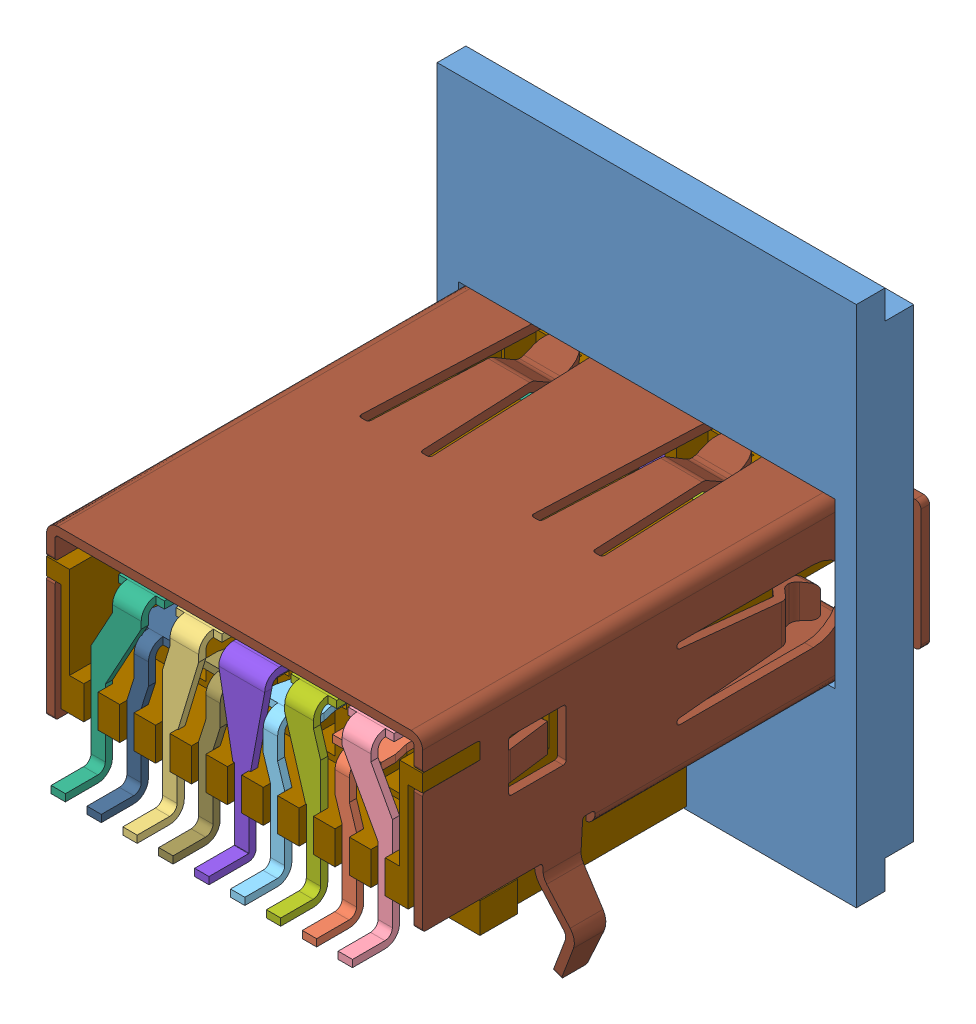
SolidWorks assembly Keystone-USB3-A, configuration Standard. Lengths in mm.
Overall size (15.1 18.2 17.8).
13 component instances, 12 part files, 3 mates.
Components (placement in the parent):
- Keystone-USB-3-Pannel-1: Keystone-USB-3-Pannel [Standard] at (-0.2593 -6.7378 17.2) size (14.6 18.2 2)
- USB3-A-1: USB3-A [Standard] at (-7.5593 2.2822 29.56) x (0 0 -1) z (0 1 0) size (17.8 15.1 10.24)
  - USB3-A-Pin-4-1: USB3-A-Pin-4 [Standard] at origin size (12.71 1.7 4.79)
  - USB3-A-Pin-8-1: USB3-A-Pin-8 [Standard] at origin size (16.44 1.6 5.89)
  - USB3-A-Pin-5-1: USB3-A-Pin-5 [Standard] at origin size (16.44 2.05 5.89)
  - USB3-A-Pin-3-1: USB3-A-Pin-3 [Standard] at origin size (12.71 1.7 4.79)
  - USB3-A-Pin-9-1: USB3-A-Pin-9 [Standard] at origin size (16.44 2.05 5.89)
  - USB3-A-Pin-6-1: USB3-A-Pin-6 [Standard] at origin size (16.44 1.6 5.89)
  - USB3-A-Pin-7-1: USB3-A-Pin-7 [Standard] at origin size (16.44 1.6 5.89)
  - USB3-A-Inner-Plastic-1: USB3-A-Inner-Plastic [Standard] at origin size (16 13.1 7.94)
  - USB3-A-Pin-1-1: USB3-A-Pin-1 [Standard] at origin size (12.71 1.7 4.79)
  - USB3-A-Outer-Shell-1: USB3-A-Outer-Shell [Standard] at origin size (16.66 15.1 10.24)
  - USB3-A-Pin-2-1: USB3-A-Pin-2 [Standard] at origin size (12.71 1.7 4.79)
Mates (geometry in assembly coordinates):
- Deckungsgleich1: coincident anti-aligned: plane of Keystone-USB-3-Pannel-1 through (-0.2593 -6.7378 17.2) normal (0 0 -1); plane of USB3-A-1/USB3-A-Outer-Shell-1 through (-7.5593 1.3622 17.2) normal (0 0 1)
- Deckungsgleich2: coincident anti-aligned: plane of Keystone-USB-3-Pannel-1 through (-1.0093 4.2222 27.2) normal (0 -1 0); plane of USB3-A-1/USB3-A-Outer-Shell-1 through (-13.7093 4.2222 17.2) normal (0 1 0)
- Deckungsgleich3: coincident anti-aligned: plane of Keystone-USB-3-Pannel-1 through (-14.1093 4.2222 27.2) normal (1 0 0); plane of USB3-A-1/USB3-A-Outer-Shell-1 through (-14.1093 3.8222 17.2) normal (-1 0 0)
